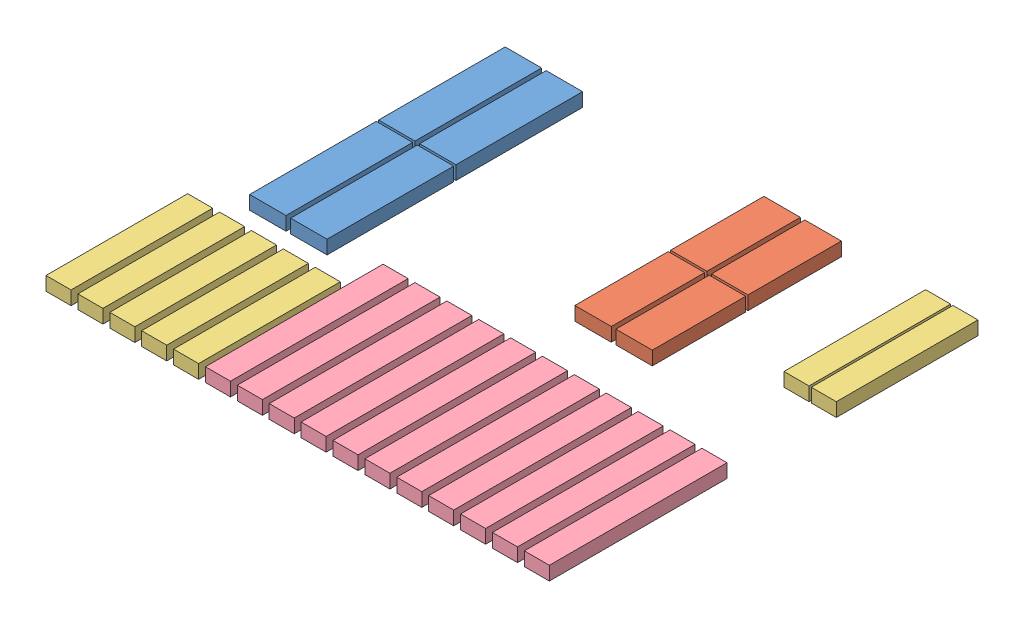
SolidWorks assembly РаскройЛ, configuration По умолчанию. Lengths in mm.
Overall size (1107.5 30 938.5).
28 component instances, 5 part files, 15 mates.
Components (placement in the parent):
- Полоса75_520-1: Полоса75_520 [По умолчанию] at (368.2077 368.8808 368.5915) (suppressed, hidden)
- Полоса75_520-2: Полоса75_520 [По умолчанию] at (458.2077 368.8808 368.5915) (suppressed, hidden)
- Полоса75_300-1: Полоса75_300 [По умолчанию] at (255.2077 368.8808 168.5915) size (80 30 278)
- Полоса75_300-2: Полоса75_300 [По умолчанию] at (255.2077 368.8808 451.5915) size (80 30 278)
- Полоса75_300-3: Полоса75_300 [По умолчанию] at (165.2077 368.8808 168.5915) size (80 30 278)
- Полоса75_300-4: Полоса75_300 [По умолчанию] at (165.2077 368.8808 451.5915) size (80 30 278)
- Полоса75_200-1: Полоса75_200 [По умолчанию] at (733.2077 368.8808 95.5915) size (80 30 205)
- Полоса75_200-2: Полоса75_200 [По умолчанию] at (733.2077 368.8808 305.5915) size (80 30 205)
- Полоса75_200-3: Полоса75_200 [По умолчанию] at (823.2077 368.8808 95.5915) size (80 30 205)
- Полоса75_200-4: Полоса75_200 [По умолчанию] at (823.2077 368.8808 305.5915) size (80 30 205)
- Полоса50_325-1: Полоса50_325 [По умолчанию] at (1088.2077 368.8808 201.5915) size (55 30 311)
- Полоса50_325-2: Полоса50_325 [По умолчанию] at (1148.2077 368.8808 201.5915) size (55 30 311)
- Полоса50_325-3: Полоса50_325 [По умолчанию] at (165.7077 368.8808 829.0915) size (55 30 311)
- Полоса50_325-4: Полоса50_325 [По умолчанию] at (235.7077 368.8808 829.0915) size (55 30 311)
- Полоса50_325-5: Полоса50_325 [По умолчанию] at (305.7077 368.8808 829.0915) size (55 30 311)
- Полоса50_325-6: Полоса50_325 [По умолчанию] at (375.7077 368.8808 829.0915) size (55 30 311)
- Полоса50_390-1: Полоса50_390 [По умолчанию] at (444.2077 368.8808 827.5915) size (55 30 390)
- Полоса50_390-2: Полоса50_390 [По умолчанию] at (514.2077 368.8808 827.5915) size (55 30 390)
- Полоса50_390-3: Полоса50_390 [По умолчанию] at (584.2077 368.8808 827.5915) size (55 30 390)
- Полоса50_390-4: Полоса50_390 [По умолчанию] at (654.2077 368.8808 827.5915) size (55 30 390)
- Полоса50_390-5: Полоса50_390 [По умолчанию] at (724.2077 368.8808 827.5915) size (55 30 390)
- Полоса50_390-6: Полоса50_390 [По умолчанию] at (794.2077 368.8808 827.5915) size (55 30 390)
- Полоса50_390-7: Полоса50_390 [По умолчанию] at (864.2077 368.8808 827.5915) size (55 30 390)
- Полоса50_390-8: Полоса50_390 [По умолчанию] at (934.2077 368.8808 827.5915) size (55 30 390)
- Полоса50_390-9: Полоса50_390 [По умолчанию] at (1004.2077 368.8808 827.5915) size (55 30 390)
- Полоса50_390-10: Полоса50_390 [По умолчанию] at (1074.2077 368.8808 827.5915) size (55 30 390)
- Полоса50_390-11: Полоса50_390 [По умолчанию] at (1144.2077 368.8808 827.5915) size (55 30 390)
- Полоса50_325-8: Полоса50_325 [По умолчанию] at (95.7077 368.8808 829.0915) size (55 30 311)
Mates (geometry in assembly coordinates):
- Совпадение1: coincident aligned: plane of Полоса75_520-1 through (368.2077 398.8808 -109.4085) normal (0 0 -1); plane of Полоса75_300-1 through (255.2077 398.8808 -109.4085) normal (0 0 -1)
- Расстояние1: distance = 33 mm anti-aligned: plane of Полоса75_520-1 through (368.2077 398.8808 368.5915) normal (-1 0 0); plane of Полоса75_300-1 through (335.2077 398.8808 168.5915) normal (1 0 0)
- Совпадение3: coincident aligned: plane of Полоса75_520-1 through (368.2077 398.8808 368.5915) normal (0 1 0); plane of Полоса75_300-1 through (255.2077 398.8808 168.5915) normal (0 1 0)
- Совпадение4: coincident aligned: plane of Полоса75_520-1 through (368.2077 398.8808 368.5915) normal (0 1 0); plane of Полоса75_200-1 through (733.2077 398.8808 95.5915) normal (0 1 0)
- Совпадение5: coincident aligned: plane of ? through (638.2077 398.8808 -109.4085) normal (0 0 -1); plane of Полоса75_200-1 through (733.2077 398.8808 -109.4085) normal (0 0 -1)
- Расстояние2: distance = 15 mm anti-aligned: plane of Полоса75_200-1 through (733.2077 398.8808 95.5915) normal (-1 0 0); plane of ? through (718.2077 398.8808 368.5915) normal (1 0 0)
- Совпадение7: coincident aligned: plane of Полоса75_520-1 through (368.2077 398.8808 368.5915) normal (0 1 0); plane of Полоса50_325-1 through (1088.2077 398.8808 201.5915) normal (0 1 0)
- Совпадение8: coincident aligned: plane of Полоса75_520-1 through (368.2077 398.8808 -109.4085) normal (0 0 -1); plane of Полоса50_325-1 through (1088.2077 398.8808 -109.4085) normal (0 0 -1)
- Расстояние3: distance = 720 mm aligned: plane of Полоса50_325-1 through (1088.2077 398.8808 201.5915) normal (-1 0 0); plane of Полоса75_520-1 through (368.2077 398.8808 368.5915) normal (-1 0 0)
- Совпадение10: coincident aligned: plane of Полоса75_520-1 through (368.2077 398.8808 368.5915) normal (0 1 0); plane of Полоса50_325-3 through (165.7077 398.8808 829.0915) normal (0 1 0)
- Расстояние4: distance = 202.5 mm aligned: plane of Полоса50_325-3 through (165.7077 398.8808 829.0915) normal (-1 0 0); plane of Полоса75_520-1 through (368.2077 398.8808 368.5915) normal (-1 0 0)
- Расстояние5: distance = 627.5 mm aligned: plane of Полоса50_325-3 through (165.7077 398.8808 518.0915) normal (0 0 -1); plane of Полоса75_520-1 through (368.2077 398.8808 -109.4085) normal (0 0 -1)
- Совпадение11: coincident aligned: plane of Полоса75_520-1 through (368.2077 398.8808 368.5915) normal (0 1 0); plane of Полоса50_390-1 through (444.2077 398.8808 827.5915) normal (0 1 0)
- Расстояние6: distance = 547 mm aligned: plane of Полоса75_520-1 through (368.2077 398.8808 -109.4085) normal (0 0 -1); plane of Полоса50_390-1 through (444.2077 398.8808 437.5915) normal (0 0 -1)
- Расстояние7: distance = 76 mm aligned: plane of Полоса75_520-1 through (368.2077 398.8808 368.5915) normal (-1 0 0); plane of Полоса50_390-1 through (444.2077 398.8808 827.5915) normal (-1 0 0)
